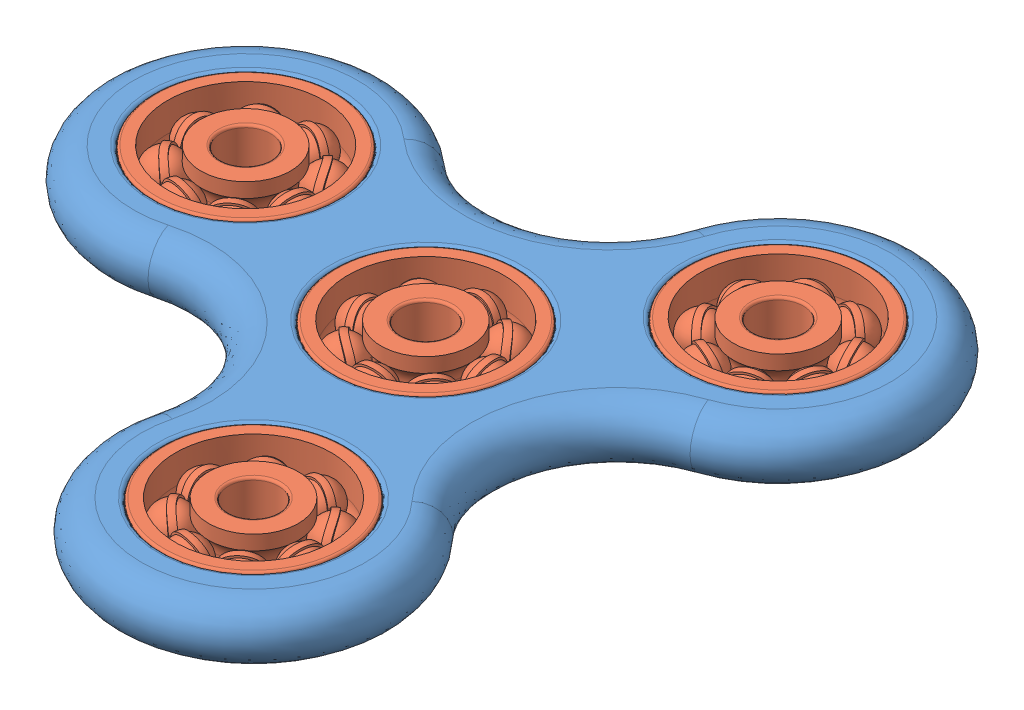
SolidWorks assembly Assem1, configuration Default. Lengths in mm.
Overall size (97.75 7 102.78).
5 component instances, 2 part files, 9 mates.
Components (placement in the parent):
- part1-1: part1 [Default] at (4.5875 -0.8264 1.543) x (0.246429 0 -0.969161) z (0.969161 0 0.246429) size (85.96 7 79)
- angular contact ball bearing_68_bsi-35: angular contact ball bearing_68_bsi [BS 6267 ABB - 36 - Full,DE,AC,Full_68] at (-24.4873 -0.8264 -5.8499) x (0 -1 0) z (-0.809909 0 0.586556) size (7 22 22)
- angular contact ball bearing_68_bsi-36: angular contact ball bearing_68_bsi [BS 6267 ABB - 36 - Full,DE,AC,Full_68] at (12.7225 -0.8264 30.419) x (0 -1 0) z (-0.801176 0 0.598429) size (7 22 22)
- angular contact ball bearing_68_bsi-37: angular contact ball bearing_68_bsi [BS 6267 ABB - 36 - Full,DE,AC,Full_68] at (4.5875 -0.8264 1.543) x (0 -1 0) z (-0.64572 0 0.763574) size (7 22 22)
- angular contact ball bearing_68_bsi-38: angular contact ball bearing_68_bsi [BS 6267 ABB - 36 - Full,DE,AC,Full_68] at (25.5273 -0.8264 -19.9401) x (0 -1 0) z (0.360267 0 -0.932849) size (7 22 22)
Mates (geometry in assembly coordinates):
- Concentric8: concentric aligned: cylinder of part1-1 through (4.5875 2.6736 1.543) axis (0 -1 0) radius 11; cylinder of angular contact ball bearing_68_bsi-37 through (4.5875 19.8111 1.543) axis (0 -1 0) radius 3
- Concentric13: concentric aligned: cylinder of part1-1 through (12.7225 2.6736 30.419) axis (0 -1 0) radius 11; cylinder of angular contact ball bearing_68_bsi-36 through (12.7225 19.8111 30.419) axis (0 -1 0) radius 11
- Coincident5: coincident anti-aligned: plane of part1-1 through (4.5875 2.6736 1.543) normal (0 1 0); circle of angular contact ball bearing_68_bsi-36
- Concentric14: concentric aligned: cylinder of part1-1 through (4.5875 2.6736 1.543) axis (0 -1 0) radius 11; cylinder of angular contact ball bearing_68_bsi-37 through (4.5875 19.8111 1.543) axis (0 -1 0) radius 11
- Coincident6: coincident aligned: plane of part1-1 through (4.5875 2.6736 1.543) normal (0 1 0); plane of angular contact ball bearing_68_bsi-37 through (8.7108 2.6736 5.0299) normal (0 1 0)
- Concentric15: concentric aligned: cylinder of part1-1 through (-24.4873 2.6736 -5.8499) axis (0 -1 0) radius 11; cylinder of angular contact ball bearing_68_bsi-35 through (-24.4873 19.8111 -5.8499) axis (0 -1 0) radius 11
- Coincident7: coincident anti-aligned: plane of part1-1 through (4.5875 2.6736 1.543) normal (0 1 0); circle of angular contact ball bearing_68_bsi-35
- Concentric16: concentric aligned: cylinder of part1-1 through (25.5273 2.6736 -19.9401) axis (0 -1 0) radius 11; cylinder of angular contact ball bearing_68_bsi-38 through (25.5273 19.8111 -19.9401) axis (0 -1 0) radius 11
- Coincident8: coincident anti-aligned: plane of part1-1 through (4.5875 2.6736 1.543) normal (0 1 0); circle of angular contact ball bearing_68_bsi-38
